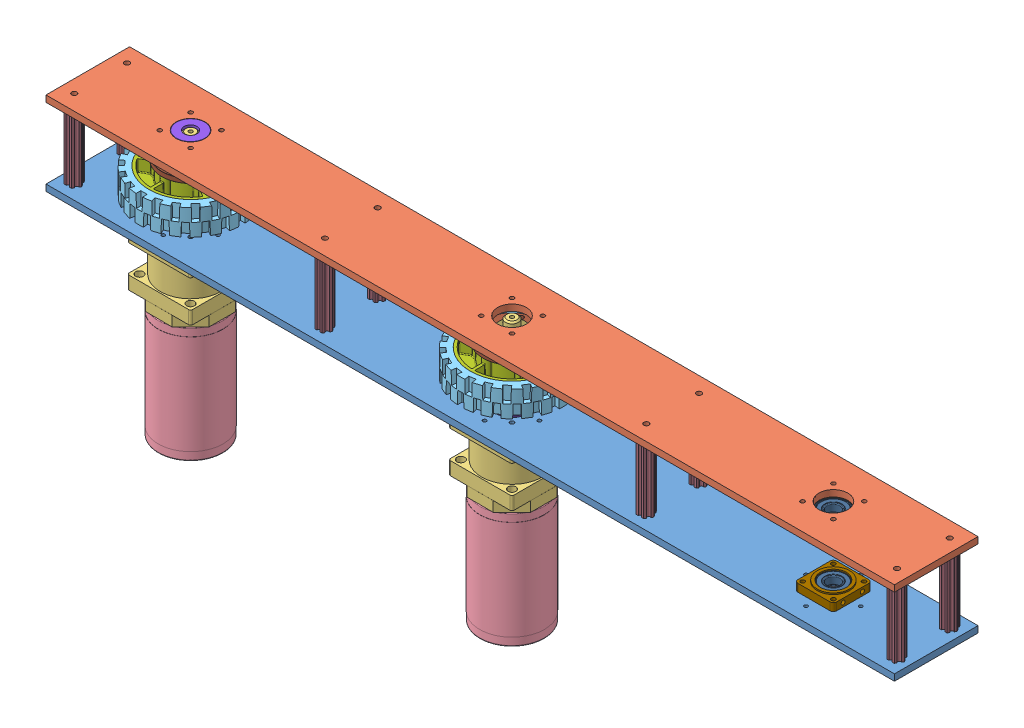
SolidWorks assembly Test Drivetrain missing front wheel, configuration Default. Lengths in mm.
Overall size (838.2 265.47 101.6).
36 component instances, 13 part files, 0 mates.
Components (placement in the parent):
- Part 1-1: Part 1 [Default] at (-38.5457 30.6125 50.2243) size (838.2 6.35 82.55)
- Part 1_2-1: Part 1_2 [Default] at (-38.5457 106.8125 50.2243) size (838.2 6.35 82.55)
- Part 5-1: Part 5 [Default] at (-366.229 11.2625 55.6796) x (0 0 -1) z (1 0 0) size (62.86 145.05 62.86)
- Part 5-2: Part 5 [Default] at (-44.001 11.2625 40.041) size (62.86 145.05 62.86)
- am-0255 2.5inch CIM Motor-1: am-0255 2.5inch CIM Motor [Default] at (-391.6057 -58.2875 159.5205) x (1 0 0) z (0 1 0) size (64.01 64.01 154.94)
- am-0255 2.5inch CIM Motor-2: am-0255 2.5inch CIM Motor [Default] at (-74.1057 -58.2875 159.5205) x (1 0 0) z (0 1 0) size (64.01 64.01 154.94)
- 4 in tread-1: 4 in tread [Default] at (-356.0457 63.8121 50.2243) x (0 1 0) z (0 0 1) size (25.4 101.6 101.6)
- 4in 2013 Hub-1: 4in 2013 Hub [Default] at (-356.0457 63.8121 50.2243) x (0 1 0) z (1 0 0) size (17.56 82.55 82.55)
- 4in 2013 Hub_2-1: 4in 2013 Hub_2 [Default] at (-356.0457 63.8121 50.2243) x (0 1 0) z (1 0 0) size (17.56 82.55 82.55)
- 4 in tread-2: 4 in tread [Default] at (-38.5457 67.1549 50.2243) x (0 -1 0) z (0 0 1) size (25.4 101.6 101.6)
- 4in 2013 Hub-2: 4in 2013 Hub [Default] at (-38.5457 67.1549 50.2243) x (0 1 0) z (1 0 0) size (17.56 82.55 82.55)
- 4in 2013 Hub_2-2: 4in 2013 Hub_2 [Default] at (-38.5457 67.1549 50.2243) x (0 1 0) z (1 0 0) size (17.56 82.55 82.55)
- am-0030 0.5''''id Flanged, Shielded Ball Bearing (FR8ZZ)-1: am-0030 0.5''''id Flanged, Shielded Ball Bearing (FR8ZZ) [Default] at (-38.5457 106.8659 50.2243) x (1 0 0) z (0 -1 0) (suppressed, hidden)
- am-0030 0.5''''id Flanged, Shielded Ball Bearing (FR8ZZ)-2: am-0030 0.5''''id Flanged, Shielded Ball Bearing (FR8ZZ) [Default] at (-38.5457 24.2092 50.2243) x (1 0 0) z (0 1 0)
- am-0030 0.5''''id Flanged, Shielded Ball Bearing (FR8ZZ)-3: am-0030 0.5''''id Flanged, Shielded Ball Bearing (FR8ZZ) [Default] at (-356.0457 106.8659 50.2243) x (1 0 0) z (0 -1 0)
- P60 bearing block-1: P60 bearing block [Default] at (263.9197 90.1331 29.6254) x (0 1 0) z (1 0 0) size (9.02 38.25 38.25)
- R8ZZ Bearing-1: R8ZZ Bearing [Default] at (299.5531 90.4506 35.1897) x (0 1 0) z (0 0 1) size (7.94 28.58 28.58)
- P60 bearing block-2: P60 bearing block [Default] at (263.9197 40.942 70.8231) x (0 -1 0) z (1 0 0) size (9.02 38.25 38.25)
- R8ZZ Bearing-2: R8ZZ Bearing [Default] at (299.5531 152.3631 35.1897) x (0 1 0) z (0 0 1) size (7.94 28.58 28.58)
- 500 Key Hub r2-1: 500 Key Hub r2 [Default] at (-356.0457 80.3856 50.2243) x (-1 0 0) z (0 1 0) size (57.15 57.15 25.4)
- 500 Key Hub r2-2: 500 Key Hub r2 [Default] at (-38.5457 50.5814 50.2243) x (1 0 0) z (0 -1 0) size (57.15 57.15 25.4)
- 500 Key Hub r2-3: 500 Key Hub r2 [Default] at (-356.0457 47.2386 50.2243) x (1 0 0) z (0 -1 0) size (57.15 57.15 25.4)
- 500 Key Hub r2-4: 500 Key Hub r2 [Default] at (-38.5457 83.7284 50.2243) x (-1 0 0) z (0 1 0) size (57.15 57.15 25.4)
- am-0030 0.5''''id Flanged, Shielded Ball Bearing (FR8ZZ)-4: am-0030 0.5''''id Flanged, Shielded Ball Bearing (FR8ZZ) [Default] at (-356.0457 24.2092 50.2243) x (1 0 0) z (0 1 0)
- 217-2736.20121205-1: 217-2736.20121205 [Default] at (-33.9325 40.4543 52.8399) x (1 0 0) z (0 1 0) size (25.39 25.4 6.35)
- 217-2736.20121205-2: 217-2736.20121205 [Default] at (-33.9325 93.8554 47.6086) x (1 0 0) z (0 -1 0) size (25.39 25.4 6.35)
- 217-2736.20121205-3: 217-2736.20121205 [Default] at (-351.4325 37.1115 52.8399) x (1 0 0) z (0 1 0) size (25.39 25.4 6.35)
- 217-2736.20121205-4: 217-2736.20121205 [Default] at (-351.4325 90.5127 47.6086) x (1 0 0) z (0 -1 0) size (25.39 25.4 6.35)
- am-churro 500 churro tube-1: am-churro 500 churro tube [Default] at (-444.9457 30.6125 76.2593) x (1 0 0) z (0 1 0) size (14.66 12.7 69.85)
- am-churro 500 churro tube-2: am-churro 500 churro tube [Default] at (-444.9457 30.6125 24.1893) x (1 0 0) z (0 1 0) size (14.66 12.7 69.85)
- am-churro 500 churro tube-3: am-churro 500 churro tube [Default] at (367.8543 30.6125 76.2593) x (1 0 0) z (0 1 0) size (14.66 12.7 69.85)
- am-churro 500 churro tube-4: am-churro 500 churro tube [Default] at (367.8543 30.6125 24.1893) x (1 0 0) z (0 1 0) size (14.66 12.7 69.85)
- am-churro 500 churro tube-5: am-churro 500 churro tube [Default] at (-197.2957 30.6125 24.1893) x (1 0 0) z (0 1 0) size (14.66 12.7 69.85)
- am-churro 500 churro tube-6: am-churro 500 churro tube [Default] at (120.2043 30.6125 76.2593) x (1 0 0) z (0 1 0) size (14.66 12.7 69.85)
- am-churro 500 churro tube-7: am-churro 500 churro tube [Default] at (120.2043 30.6125 24.1893) x (1 0 0) z (0 1 0) size (14.66 12.7 69.85)
- am-churro 500 churro tube-8: am-churro 500 churro tube [Default] at (-197.2957 30.6125 76.2593) x (1 0 0) z (0 1 0) size (14.66 12.7 69.85)
